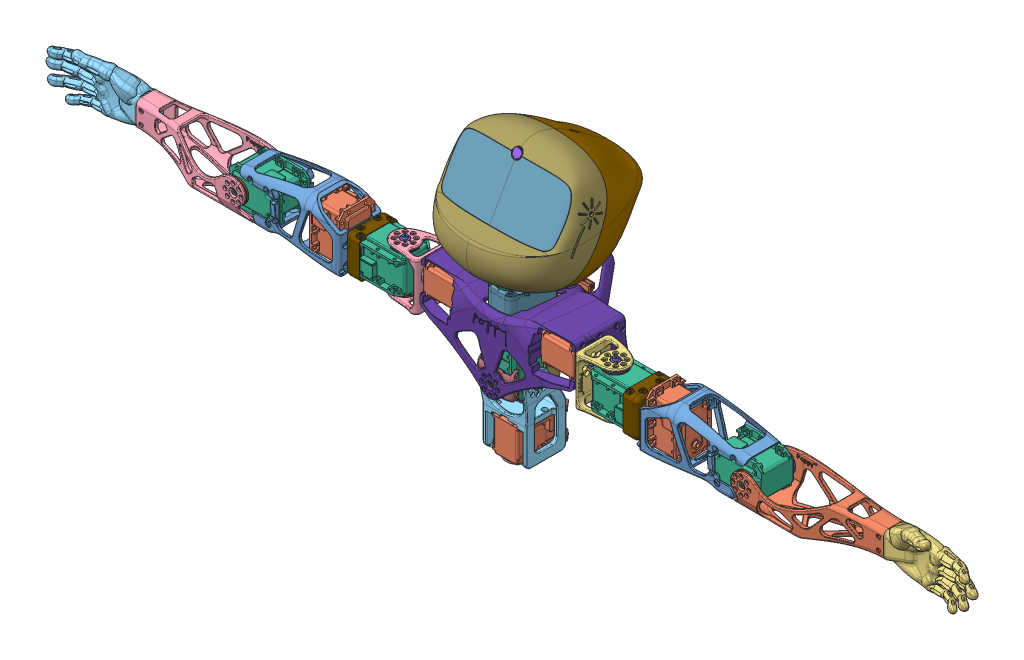
SolidWorks assembly Poppy_Humanoid, configuration Default. Lengths in mm.
Overall size (932.36 305.58 172.17).
130 component instances, 41 part files, 0 mates.
Components (placement in the parent):
- spine-1: spine [Default] at (0 138.4875 17) size (49.29 92.85 54.86)
  - MX-28(T)-2-1: MX-28(T)-2 [Default] x (1 0 0) z (0 -1 0) size (35.6 54.13 45.1)
    - WB_M2.5x8-1: WB_M2.5x8 [Default] at (0 0 25.85) x (0 0 -1) z (-0.991137 0.132843 0) size (10.5 4.5 4.5)
    - dynamixel_x28series(Défaut)-1: dynamixel_x28series(Défaut) [Default] at origin size (35.6 50.71 41.85)
    - trust_washer(Défaut)-1: trust_washer(Défaut) [Default] at (0 0 18.6) x (-0.666375 -0.745617 0) z (0.745617 -0.666375 0) size (22 0.85 22)
    - HN07-N101(Défaut)-1: HN07-N101(Défaut) [Default] at (0 0 18.5) x (1 0 0) z (0 -1 0) size (22 5.85 22)
  - spine-1: spine [Default] at (0 15 0.8) x (-1 0 0) z (0 0 -1) size (49.29 83.95 45.1)
- double_rotation(full_MX28)-1: double_rotation(full_MX28) [Default] at (0 192.4875 19.8) size (48.5 54.13 85.1)
  - MX-28(U)-6-1: MX-28(U)-6 [Default] x (0 0 1) z (1 0 0) size (35.6 54.13 48.5)
    - dynamixel_x28series(U)-1: dynamixel_x28series(U) [Default] at origin size (35.6 50.71 41.85)
    - trust_washer(U)-1: trust_washer(U) [Default] at (0 0 18.6) x (-0.666375 -0.745617 0) z (0.745617 -0.666375 0) size (22 0.85 22)
    - HN07-N101(U)-1: HN07-N101(U) [Default] at (0 0 18.5) x (1 0 0) z (0 -1 0) size (22 5.85 22)
    - WB_M2.5x8-1: WB_M2.5x8 [Default] at (0 0 25.85) x (0 0 -1) z (-0.991137 0.132843 0) size (10.5 4.5 4.5)
    - WB_M2.5x8-2: WB_M2.5x8 [Default] at (0 0 -22.65) x (0 0 1) z (-0.936501 0.350665 0) size (10.5 4.5 4.5)
    - RX28-CAP-1: RX28-CAP [Default] at (0 0 -20.35) x (-0.995735 -0.092256 0) z (0 0 -1) size (7.2 7.2 1.8)
    - MF106ZZ-1: MF106ZZ [Default] at (0 0 -20.35) x (0.888333 -0.4592 0) z (-0.4592 -0.888333 0) size (11.2 3 11.2)
    - HN07-i101-1: HN07-i101 [Default] at (0 0 -20.5) x (1 0 0) z (0 1 0) size (22 3.05 22)
  - MX-28(T)-3-1: MX-28(T)-3 [Default] at (0 0 -37) x (1 0 0) z (0 0 -1) size (35.6 54.13 45.1)
    - WB_M2.5x8-1: WB_M2.5x8 [Default] at (0 0 25.85) x (0 0 -1) z (-0.991137 0.132843 0) size (10.5 4.5 4.5)
    - dynamixel_x28series(Défaut)-1: dynamixel_x28series(Défaut) [Default] at origin size (35.6 50.71 41.85)
    - trust_washer(Défaut)-1: trust_washer(Défaut) [Default] at (0 0 18.6) x (-0.666375 -0.745617 0) z (0.745617 -0.666375 0) size (22 0.85 22)
    - HN07-N101(Défaut)-1: HN07-N101(Défaut) [Default] at (0 0 18.5) x (1 0 0) z (0 -1 0) size (22 5.85 22)
  - i101_Set(FR07)-1: i101_Set(FR07) [Default] at (0 0 21.6) x (-0.798096 0.60253 0) z (0 0 1) size (22 22 3.8)
    - RX28-CAP-1: RX28-CAP [Default] at (0 0 -0.15) size (7.2 7.2 1.8)
    - MF106ZZ-1: MF106ZZ [Default] at (0 0 -0.15) x (-0.837169 0.546944 0) z (-0.546944 -0.837169 0) size (11.2 3 11.2)
    - HN07-i101-1: HN07-i101 [Default] x (1 0 0) z (0 -1 0) size (22 3.05 22)
  - double_rotation_link(double_MX28)-1: double_rotation_link(double_MX28) [Default] at (0 -0.5 0) size (7.4 26.51 14.1)
  - double_rotation_link(double_MX28)-2: double_rotation_link(double_MX28) [Default] at (0 8.5 0) x (-1 0 0) z (0 0 1) size (7.4 26.51 14.1)
  - i101-Set_to_MX_link(MX28_compatible)-1: i101-Set_to_MX_link(MX28_compatible) [Default] x (0 0 -1) z (1 0 0) size (8.29 28.53 35.81)
- chest-1: chest [Default] at (7.2825 216.5654 -159.6611) size (167.7 95.79 102.98)
  - AX-12_18A-1: AX-12_18A [Default] at (-7.2825 38.9221 184.4611) x (-1 0 0) z (0 1 0) size (32 50.04 40.32)
    - dynamixel_AXseries-1: dynamixel_AXseries [Default] at origin size (32 50.04 38.37)
    - AX12_horn-1: AX12_horn [Default] at (0 0 19.1) x (0 1 0) z (0 0 1) size (22 22 6.7)
    - BHS_M2_6X8-1: BHS_M2_6X8 [Default] at (0 0 19.55) x (0.628847 -0.777529 0) z (-0.777529 -0.628847 0) size (5.5 9.6 5.5)
  - MX-28(T)-4-1: MX-28(T)-4 [Default] at (-65.2825 25.9221 183.4611) x (0 -1 0) z (-1 0 0) size (35.6 54.13 45.1)
    - WB_M2.5x8-1: WB_M2.5x8 [Default] at (0 0 25.85) x (0 0 -1) z (-0.991137 0.132843 0) size (10.5 4.5 4.5)
    - dynamixel_x28series(Défaut)-1: dynamixel_x28series(Défaut) [Default] at origin size (35.6 50.71 41.85)
    - trust_washer(Défaut)-1: trust_washer(Défaut) [Default] at (0 0 18.6) x (-0.666375 -0.745617 0) z (0.745617 -0.666375 0) size (22 0.85 22)
    - HN07-N101(Défaut)-1: HN07-N101(Défaut) [Default] at (0 0 18.5) x (1 0 0) z (0 -1 0) size (22 5.85 22)
  - MX-28(T)-5-1: MX-28(T)-5 [Default] at (50.7175 25.9221 183.4611) x (0 1 0) z (1 0 0) size (35.6 54.13 45.1)
    - WB_M2.5x8-1: WB_M2.5x8 [Default] at (0 0 25.85) x (0 0 -1) z (-0.991137 0.132843 0) size (10.5 4.5 4.5)
    - dynamixel_x28series(Défaut)-1: dynamixel_x28series(Défaut) [Default] at origin size (35.6 50.71 41.85)
    - trust_washer(Défaut)-1: trust_washer(Défaut) [Default] at (0 0 18.6) x (-0.666375 -0.745617 0) z (0.745617 -0.666375 0) size (22 0.85 22)
    - HN07-N101(Défaut)-1: HN07-N101(Défaut) [Default] at (0 0 18.5) x (1 0 0) z (0 -1 0) size (22 5.85 22)
  - chest-1: chest [Default] at (-7.2825 -24.0779 121.9611) size (157.02 95.79 102.98)
- shoulder_x-1: shoulder_x [Default] at (119.9166 235.6125 35.5145) x (0 0 -1) z (0 1 0) size (38.6 59.63 48.85)
  - MX-28(U)-7-1: MX-28(U)-7 [Default] at (11.7145 14.4166 -1.625) size (35.6 54.13 48.5)
    - dynamixel_x28series(U)-1: dynamixel_x28series(U) [Default] at origin size (35.6 50.71 41.85)
    - trust_washer(U)-1: trust_washer(U) [Default] at (0 0 18.6) x (-0.666375 -0.745617 0) z (0.745617 -0.666375 0) size (22 0.85 22)
    - HN07-N101(U)-1: HN07-N101(U) [Default] at (0 0 18.5) x (1 0 0) z (0 -1 0) size (22 5.85 22)
    - WB_M2.5x8-1: WB_M2.5x8 [Default] at (0 0 25.85) x (0 0 -1) z (-0.991137 0.132843 0) size (10.5 4.5 4.5)
    - WB_M2.5x8-2: WB_M2.5x8 [Default] at (0 0 -22.65) x (0 0 1) z (-0.936501 0.350665 0) size (10.5 4.5 4.5)
    - RX28-CAP-1: RX28-CAP [Default] at (0 0 -20.35) x (-0.995735 -0.092256 0) z (0 0 -1) size (7.2 7.2 1.8)
    - MF106ZZ-1: MF106ZZ [Default] at (0 0 -20.35) x (0.888333 -0.4592 0) z (-0.4592 -0.888333 0) size (11.2 3 11.2)
    - HN07-i101-1: HN07-i101 [Default] at (0 0 -20.5) x (1 0 0) z (0 1 0) size (22 3.05 22)
  - arm_connector-1: arm_connector [Default] at (11.7145 -28.1834 -11.625) size (38.6 17.77 41.99)
- upper_arm(double_MX-28)-1: upper_arm(double_MX-28) [Default] at (222.8165 235.6388 -24.353) x (0 0 -1) z (0 1 0) size (49.68 127.28 61.97)
  - MX-28(T)-6-1: MX-28(T)-6 [Default] at (-48.153 54.2165 -11.6513) x (1 0 0) z (0 1 0) size (35.6 54.13 45.1)
    - WB_M2.5x8-1: WB_M2.5x8 [Default] at (0 0 25.85) x (0 0 -1) z (-0.991137 0.132843 0) size (10.5 4.5 4.5)
    - dynamixel_x28series(Défaut)-1: dynamixel_x28series(Défaut) [Default] at origin size (35.6 50.71 41.85)
    - trust_washer(Défaut)-1: trust_washer(Défaut) [Default] at (0 0 18.6) x (-0.666375 -0.745617 0) z (0.745617 -0.666375 0) size (22 0.85 22)
    - HN07-N101(Défaut)-1: HN07-N101(Défaut) [Default] at (0 0 18.5) x (1 0 0) z (0 -1 0) size (22 5.85 22)
  - MX-28(U)-8-1: MX-28(U)-8 [Default] at (-48.153 -31.6835 -1.6513) x (0 0 1) z (1 0 0) size (35.6 54.13 48.5)
    - dynamixel_x28series(U)-1: dynamixel_x28series(U) [Default] at origin size (35.6 50.71 41.85)
    - trust_washer(U)-1: trust_washer(U) [Default] at (0 0 18.6) x (-0.666375 -0.745617 0) z (0.745617 -0.666375 0) size (22 0.85 22)
    - HN07-N101(U)-1: HN07-N101(U) [Default] at (0 0 18.5) x (1 0 0) z (0 -1 0) size (22 5.85 22)
    - WB_M2.5x8-1: WB_M2.5x8 [Default] at (0 0 25.85) x (0 0 -1) z (-0.991137 0.132843 0) size (10.5 4.5 4.5)
    - WB_M2.5x8-2: WB_M2.5x8 [Default] at (0 0 -22.65) x (0 0 1) z (-0.936501 0.350665 0) size (10.5 4.5 4.5)
    - RX28-CAP-1: RX28-CAP [Default] at (0 0 -20.35) x (-0.995735 -0.092256 0) z (0 0 -1) size (7.2 7.2 1.8)
    - MF106ZZ-1: MF106ZZ [Default] at (0 0 -20.35) x (0.888333 -0.4592 0) z (-0.4592 -0.888333 0) size (11.2 3 11.2)
    - HN07-i101-1: HN07-i101 [Default] at (0 0 -20.5) x (1 0 0) z (0 1 0) size (22 3.05 22)
  - upper_arm-1: upper_arm [Default] at (-48.153 -31.6835 -1.6513) size (47.66 107.84 61.97)
- forearm(left)-1: forearm(left) [Default] at (312.8543 225.3953 -5.788) x (0 0 -1) z (0 1 0) size (55.2 228.71 65.03)
  - forearm(MX28-left)-1: forearm(MX28-left) [Default] at (-29.588 58.3543 8.5922) size (55.2 137.66 53.14)
  - hand(left_fake_human_like_hand)-1: hand(left_fake_human_like_hand) [Default] at (-19.088 -61.6457 4.5922) x (0 0 -1) z (0 -1 0) size (64.5 37.73 100.68)
- shoulder_x-1-1: shoulder_x-1 [Default] at (-119.9166 235.6125 12.0855) x (0 0 1) z (0 1 0) size (38.6 59.63 48.85)
  - MX-28(U)-9-1: MX-28(U)-9 [Default] at (11.7145 14.4166 -1.625) size (35.6 54.13 48.5)
    - dynamixel_x28series(U)-1: dynamixel_x28series(U) [Default] at origin size (35.6 50.71 41.85)
    - trust_washer(U)-1: trust_washer(U) [Default] at (0 0 18.6) x (-0.666375 -0.745617 0) z (0.745617 -0.666375 0) size (22 0.85 22)
    - HN07-N101(U)-1: HN07-N101(U) [Default] at (0 0 18.5) x (1 0 0) z (0 -1 0) size (22 5.85 22)
    - WB_M2.5x8-1: WB_M2.5x8 [Default] at (0 0 25.85) x (0 0 -1) z (-0.991137 0.132843 0) size (10.5 4.5 4.5)
    - WB_M2.5x8-2: WB_M2.5x8 [Default] at (0 0 -22.65) x (0 0 1) z (-0.936501 0.350665 0) size (10.5 4.5 4.5)
    - RX28-CAP-1: RX28-CAP [Default] at (0 0 -20.35) x (-0.995735 -0.092256 0) z (0 0 -1) size (7.2 7.2 1.8)
    - MF106ZZ-1: MF106ZZ [Default] at (0 0 -20.35) x (0.888333 -0.4592 0) z (-0.4592 -0.888333 0) size (11.2 3 11.2)
    - HN07-i101-1: HN07-i101 [Default] at (0 0 -20.5) x (1 0 0) z (0 1 0) size (22 3.05 22)
  - arm_connector-1: arm_connector [Default] at (11.7145 -28.1834 -11.625) size (38.6 17.77 41.99)
- upper_arm(double-MX-28_Right)-1: upper_arm(double-MX-28_Right) [Default] at (-222.8165 235.6388 71.953) x (0 0 1) z (0 1 0) size (49.68 127.28 61.97)
  - MX-28(T)-7-1: MX-28(T)-7 [Default] at (-48.153 54.2165 -11.6513) x (1 0 0) z (0 1 0) size (35.6 54.13 45.1)
    - WB_M2.5x8-1: WB_M2.5x8 [Default] at (0 0 25.85) x (0 0 -1) z (-0.991137 0.132843 0) size (10.5 4.5 4.5)
    - dynamixel_x28series(Défaut)-1: dynamixel_x28series(Défaut) [Default] at origin size (35.6 50.71 41.85)
    - trust_washer(Défaut)-1: trust_washer(Défaut) [Default] at (0 0 18.6) x (-0.666375 -0.745617 0) z (0.745617 -0.666375 0) size (22 0.85 22)
    - HN07-N101(Défaut)-1: HN07-N101(Défaut) [Default] at (0 0 18.5) x (1 0 0) z (0 -1 0) size (22 5.85 22)
  - MX-28(U)-10-1: MX-28(U)-10 [Default] at (-48.153 -31.6835 -1.6513) x (0 0 -1) z (-1 0 0) size (35.6 54.13 48.5)
    - dynamixel_x28series(U)-1: dynamixel_x28series(U) [Default] at origin size (35.6 50.71 41.85)
    - trust_washer(U)-1: trust_washer(U) [Default] at (0 0 18.6) x (-0.666375 -0.745617 0) z (0.745617 -0.666375 0) size (22 0.85 22)
    - HN07-N101(U)-1: HN07-N101(U) [Default] at (0 0 18.5) x (1 0 0) z (0 -1 0) size (22 5.85 22)
    - WB_M2.5x8-1: WB_M2.5x8 [Default] at (0 0 -22.65) x (0 0 1) z (-0.936501 0.350665 0) size (10.5 4.5 4.5)
    - WB_M2.5x8-2: WB_M2.5x8 [Default] at (0 0 25.85) x (0 0 -1) z (-0.991137 0.132843 0) size (10.5 4.5 4.5)
    - RX28-CAP-1: RX28-CAP [Default] at (0 0 -20.35) x (-0.995735 -0.092256 0) z (0 0 -1) size (7.2 7.2 1.8)
    - MF106ZZ-1: MF106ZZ [Default] at (0 0 -20.35) x (0.888333 -0.4592 0) z (-0.4592 -0.888333 0) size (11.2 3 11.2)
    - HN07-i101-1: HN07-i101 [Default] at (0 0 -20.5) x (1 0 0) z (0 1 0) size (22 3.05 22)
  - upper_arm-1: upper_arm [Default] at (-48.153 -31.6835 -1.6513) size (47.66 107.84 61.97)
- forearm(right)-1: forearm(right) [Default] at (-312.8543 225.3953 53.388) x (0 0 1) z (0 1 0) size (55.2 228.71 65.03)
  - forearm(MX-28-right)-1: forearm(MX-28-right) [Default] at (-29.588 58.3543 8.5922) size (55.2 137.66 53.14)
  - hand(right_fake_human_like_hand)-1: hand(right_fake_human_like_hand) [Default] at (-40.0905 -61.6457 4.5922) x (0 0 -1) z (0 -1 0) size (59.65 36.84 100.68)
- head-1: head [Default] at (0 296.4875 24.8) x (1 0 0) z (0 0.34202 0.939693) size (152.35 129.81 135.97)
  - AX-12_18A-1-1: AX-12_18A-1 [Default] x (0 0.939693 0.34202) z (1 0 0) size (32 50.04 40.32)
    - dynamixel_AXseries-1: dynamixel_AXseries [Default] at origin size (32 50.04 38.37)
    - AX12_horn-1: AX12_horn [Default] at (0 0 19.1) x (0 1 0) z (0 0 1) size (22 22 6.7)
    - BHS_M2_6X8-1: BHS_M2_6X8 [Default] at (0 0 19.55) x (0.628847 -0.777529 0) z (-0.777529 -0.628847 0) size (5.5 9.6 5.5)
  - Videw_JDEPC-OV04(170_FOV_lens)-1: Videw_JDEPC-OV04(170_FOV_lens) [Default] at (0 79.5531 9.1743) x (1 0 0) z (0 0.162719 0.986672) size (60.45 10 12.9)
    - Videw_JDEPC-OV04-1: Videw_JDEPC-OV04 [Default] at origin size (60 8 0.6)
    - SM05B-SRSS-TB-1: SM05B-SRSS-TB [Default] at (-23.7 0 0.6) x (0 -1 0) z (-1 0 0) size (7 2.9 4.95)
    - 170_FOV_lens-1: 170_FOV_lens [Default] at (0 0 0.6) size (10 10 12.3)
  - head_back-1: head_back [Default] at origin size (139.97 128.52 115.71)
  - Odroid_U3-1: Odroid_U3 [Default] at (41.5 40.9083 -63.8082) x (1 0 0) z (0 -0.087156 -0.996195) size (83 21.55 48.75)
  - fake_manga_screen-1: fake_manga_screen [Default] at (0 46.1109 21.48) x (1 0 0) z (0 0.162719 0.986672) size (106 70.75 3.7)
  - head_face-1: head_face [Default] at origin size (137.8 118.1 101.78)
  - screen_support-1: screen_support [Default] at origin size (119.01 63.24 19.97)
  - screen-1: screen [Default] at origin size (152.35 100.2 22.24)
  - camera_support-1: camera_support [Default] at (0 0.0163 0.0987) size (81.74 18.94 5.38)
  - VisatonK20.40_speaker-1: VisatonK20.40_speaker [Default] at (-59.643 48.4618 4.5746) x (-0.088219 -0.989732 0.112468) z (-0.984948 0.103522 0.138425) size (40 20 7.34)
  - VisatonK20.40_speaker-2: VisatonK20.40_speaker [Default] at (59.643 48.4618 4.5746) x (0.088219 -0.989732 0.112468) z (0.984948 0.103522 0.138425) size (40 20 7.34)
  - speaker_left-1: speaker_left [Default] at origin size (22.34 61.46 49.54)
  - speaker_right-1: speaker_right [Default] at origin size (22.34 61.46 49.54)
  - 9DOF-Razor-v23-1: 9DOF-Razor-v23 [Default] at (0 23.915 -2) size (41 7.1 28)
- SMPS2Dynamixel-2: SMPS2Dynamixel [Default] at (0 215.4875 -42.45) x (-1 0 0) z (0 0 -1) size (28 54 8.4)
- shoulder(MX-28_Left)-1: shoulder(MX-28_Left) [Default] at (51.5 233.9875 23.8) x (1 0 0) z (0 1 0) size (41.1 39.63 50.34)
- shoulder(MX-28_Right)-1: shoulder(MX-28_Right) [Default] at (-105.5 233.9875 23.8) x (1 0 0) z (0 1 0) size (41.1 39.63 50.34)
- neck-1: neck [Default] at (0 296.4875 24.8) size (48.14 31.5 23.18)
